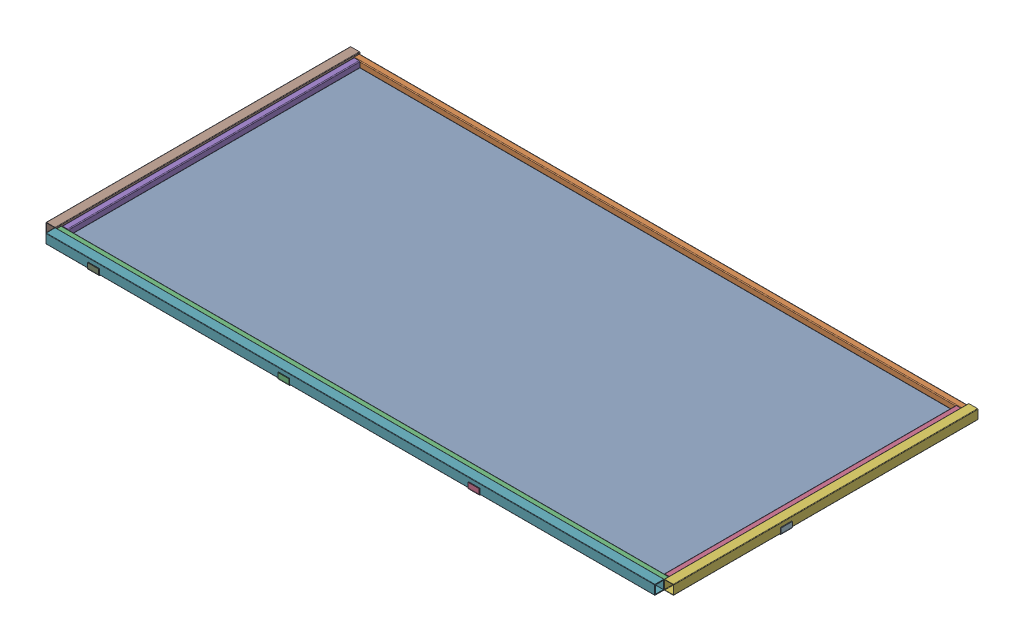
SolidWorks assembly Roof Assembly, configuration Default. Lengths in mm.
Overall size (2520.95 41.27 1263.65).
16 component instances, 6 part files, 34 mates.
Components (placement in the parent):
- Polycarbonate-1: Polycarbonate [8574K75] at (-1219.2 3.175 -609.6) x (1 0 0) z (0 -1 0) size (2438.4 1219.2 6.35)
- 8ft 1in Steel Bar-1: 8ft 1in Steel Bar [1471T534] at (-1219.2 19.05 -1206.5) x (0 0 1) z (-1 0 0) size (25.4 25.4 2438.4)
- 8ft 1in Steel Bar-2: 8ft 1in Steel Bar [1471T534] at (-1219.2 19.05 -12.7) x (0 0 1) z (-1 0 0) size (25.4 25.4 2438.4)
- 46in 1in Steel Bar-1: 46in 1in Steel Bar [1471T532] at (-12.7 19.05 -635) size (25.4 25.4 1168.4)
- 46in 1in Steel Bar-2: 46in 1in Steel Bar [1471T532] at (-2425.7 19.05 -635) size (25.4 25.4 1168.4)
- 4ft 1.5in Steel Bar-1: 4ft 1.5in Steel Bar [6527K573] at (19.05 19.05 -304.8) x (0 0 -1) z (1 0 0) size (1219.2 38.1 38.1)
- 8ft 1.5in Steel Bar-1: 8ft 1.5in Steel Bar [1984N13] at (-1219.2 19.05 19.05) x (0 0 1) z (-1 0 0) size (38.1 38.1 2438.4)
- 4ft 1.5in Steel Bar-3: 4ft 1.5in Steel Bar [6527K573] at (-2457.45 19.05 -304.8) x (0 0 -1) z (0 -1 0) size (1219.2 38.1 38.1)
- Corner Bracket-1: Corner Bracket [2313N38] at (-2246.5399 -3.175 -9.525) x (0 1 0) z (0 0 -1) size (25.4 44.45 50.8)
- Corner Bracket-2: Corner Bracket [2313N38] at (-2246.5399 -3.175 -1171.575) x (0 1 0) z (0 0 1) size (25.4 44.45 50.8)
- Corner Bracket-7: Corner Bracket [2313N38] at (-2428.875 -3.175 -449.8508) x (0 1 0) z (1 0 0) size (25.4 44.45 50.8)
- Corner Bracket-8: Corner Bracket [2313N38] at (-9.525 -3.175 -449.8508) x (0 1 0) z (-1 0 0) size (25.4 44.45 50.8)
- Corner Bracket-3: Corner Bracket [2313N38] at (-1484.5399 -3.175 -1171.575) x (0 1 0) z (0 0 1) size (25.4 44.45 50.8)
- Corner Bracket-4: Corner Bracket [2313N38] at (-722.5399 -3.175 -1171.575) x (0 1 0) z (0 0 1) size (25.4 44.45 50.8)
- Corner Bracket-5: Corner Bracket [2313N38] at (-1484.5399 -3.175 -9.525) x (0 1 0) z (0 0 -1) size (25.4 44.45 50.8)
- Corner Bracket-6: Corner Bracket [2313N38] at (-722.5399 -3.175 -9.525) x (0 1 0) z (0 0 -1) size (25.4 44.45 50.8)
Mates (geometry in assembly coordinates):
- Coincident1: coincident anti-aligned: plane of 8574K75_Clear Impact-Resistant Polycarbonate-1 through (-1219.2 0 -609.6) normal (0 -1 0)
- Coincident2: coincident aligned: plane of 8574K75_Clear Impact-Resistant Polycarbonate-1 through (-2438.4 0 0) normal (0 0 1)
- Coincident3: coincident aligned: plane of 8574K75_Clear Impact-Resistant Polycarbonate-1 through (0 0 -1219.2) normal (1 0 0)
- Coincident4: coincident anti-aligned: plane of 8574K75_Clear Impact-Resistant Polycarbonate-1 through (-1219.2 6.35 -609.6) normal (0 1 0); plane of 8ft Steel Bar-1 through (-2438.4 6.35 -1193.8) normal (0 -1 0)
- Coincident6: coincident aligned: plane of 8574K75_Clear Impact-Resistant Polycarbonate-1 through (0 0 -1219.2) normal (1 0 0); plane of 8ft Steel Bar-1 through (0 19.05 -1206.5) normal (1 0 0)
- Coincident7: coincident aligned: plane of 8ft Steel Bar-1 through (-2438.4 31.75 -1193.8) normal (0 1 0); plane of 46in Steel Bar-1 through (0 31.75 -25.4) normal (0 1 0)
- Coincident8: coincident aligned: plane of 8574K75_Clear Impact-Resistant Polycarbonate-1 through (-2438.4 0 -1219.2) normal (0 0 -1); plane of 8ft Steel Bar-1 through (-2438.4 6.35 -1219.2) normal (0 0 -1)
- Coincident9: coincident anti-aligned: plane of 8ft Steel Bar-1 through (-2438.4 6.35 -1193.8) normal (0 0 1); plane of 46in Steel Bar-1 through (-25.4 6.35 -1193.8) normal (0 0 -1)
- Coincident10: coincident aligned: plane of 8ft Steel Bar-1 through (0 19.05 -1206.5) normal (1 0 0); plane of 46in Steel Bar-1 through (0 6.35 -25.4) normal (1 0 0)
- Coincident11: coincident anti-aligned: plane of 8574K75_Clear Impact-Resistant Polycarbonate-1 through (-1219.2 6.35 -609.6) normal (0 1 0); plane of 8ft Steel Bar-2 through (-2438.4 6.35 0) normal (0 -1 0)
- Coincident12: coincident anti-aligned: plane of 8574K75_Clear Impact-Resistant Polycarbonate-1 through (-1219.2 6.35 -609.6) normal (0 1 0); plane of 46in Steel Bar-2 through (-2413 6.35 -25.4) normal (0 -1 0)
- Coincident13: coincident aligned: plane of 8ft Steel Bar-1 through (-2438.4 19.05 -1206.5) normal (-1 0 0); plane of 46in Steel Bar-2 through (-2438.4 6.35 -25.4) normal (-1 0 0)
- Coincident14: coincident anti-aligned: plane of 8ft Steel Bar-1 through (-2438.4 6.35 -1193.8) normal (0 0 1); plane of 46in Steel Bar-2 through (-2438.4 6.35 -1193.8) normal (0 0 -1)
- Coincident15: coincident anti-aligned: plane of 8ft Steel Bar-2 through (-2438.4 6.35 -25.4) normal (0 0 -1); plane of 46in Steel Bar-1 through (-12.7 19.05 -25.4) normal (0 0 1)
- Coincident16: coincident aligned: plane of 8ft Steel Bar-2 through (0 19.05 -12.7) normal (1 0 0); plane of 46in Steel Bar-1 through (0 6.35 -25.4) normal (1 0 0)
- Coincident17: coincident anti-aligned: plane of 46in Steel Bar-1 through (0 6.35 -25.4) normal (1 0 0); plane of 6527K573_Low-Carbon Steel Rectangular Tube-1 through (0 1.905 -1219.2) normal (-1 0 0)
- Coincident18: coincident aligned: plane of 8574K75_Clear Impact-Resistant Polycarbonate-1 through (-1219.2 0 -609.6) normal (0 -1 0); plane of 6527K573_Low-Carbon Steel Rectangular Tube-1 through (1.905 0 -1219.2) normal (0 -1 0)
- Coincident19: coincident aligned: plane of 8ft Steel Bar-2 through (-2438.4 6.35 0) normal (0 0 1); plane of 6527K573_Low-Carbon Steel Rectangular Tube-1 through (0 38.1 0) normal (0 0 1)
- Coincident20: coincident aligned: plane of 8574K75_Clear Impact-Resistant Polycarbonate-1 through (-1219.2 0 -609.6) normal (0 -1 0); plane of 1984N13_Weld-Together Framing Rail-1 through (-2438.4 0 0) normal (0 -1 0)
- Coincident21: coincident anti-aligned: plane of 8ft Steel Bar-2 through (-2438.4 6.35 0) normal (0 0 1); plane of 1984N13_Weld-Together Framing Rail-1 through (-2438.4 0 0) normal (0 0 -1)
- Coincident22: coincident aligned: plane of 8ft Steel Bar-2 through (-2438.4 19.05 -12.7) normal (-1 0 0); plane of 1984N13_Weld-Together Framing Rail-1 through (-2438.4 19.05 19.05) normal (-1 0 0)
- Coincident23: coincident anti-aligned: plane of 46in Steel Bar-2 through (-2438.4 6.35 -25.4) normal (-1 0 0); plane of 6527K573_Low-Carbon Steel Rectangular Tube-3 through (-2438.4 36.195 -1219.2) normal (1 0 0)
- Coincident25: coincident aligned: plane of 8ft Steel Bar-1 through (-2438.4 6.35 -1219.2) normal (0 0 -1); plane of 6527K573_Low-Carbon Steel Rectangular Tube-3 through (-2474.595 36.195 -1219.2) normal (0 0 -1)
- Coincident26: coincident aligned: plane of 8574K75_Clear Impact-Resistant Polycarbonate-1 through (-1219.2 0 -609.6) normal (0 -1 0); plane of 6527K573_Low-Carbon Steel Rectangular Tube-3 through (-2474.595 0 -1219.2) normal (0 -1 0)
- Coincident27: coincident anti-aligned: plane of 8ft 1.5in Steel Bar-1 through (-2438.4 0 38.1) normal (0 0 1); plane of Corner Bracket-1 through (-2268.7649 -3.175 38.1) normal (0 0 -1)
- Coincident28: coincident anti-aligned: plane of Polycarbonate-1 through (-1219.2 0 -609.6) normal (0 -1 0); plane of Corner Bracket-1 through (-2268.7649 0 -9.525) normal (0 1 0)
- Coincident29: coincident anti-aligned: plane of 8ft 1in Steel Bar-1 through (-2438.4 6.35 -1219.2) normal (0 0 -1); plane of Corner Bracket-2 through (-2224.3149 -3.175 -1219.2) normal (0 0 1)
- Coincident30: coincident anti-aligned: plane of Polycarbonate-1 through (-1219.2 0 -609.6) normal (0 -1 0); plane of Corner Bracket-2 through (-2224.3149 0 -1171.575) normal (0 1 0)
- Coincident31: coincident aligned: plane of Corner Bracket-1 through (-2268.7649 -3.175 38.1) normal (-1 0 0); plane of Corner Bracket-2 through (-2268.7649 -3.175 -1219.2) normal (-1 0 0)
- Coincident32: coincident anti-aligned: plane of Polycarbonate-1 through (-1219.2 0 -609.6) normal (0 -1 0); plane of Corner Bracket-8 through (-9.525 0 -427.6258) normal (0 1 0)
- Coincident33: coincident anti-aligned: plane of 4ft 1.5in Steel Bar-1 through (38.1 1.905 -1219.2) normal (1 0 0); plane of Corner Bracket-8 through (38.1 -3.175 -427.6258) normal (-1 0 0)
- Coincident34: coincident anti-aligned: plane of Polycarbonate-1 through (-1219.2 0 -609.6) normal (0 -1 0); plane of Corner Bracket-7 through (-2428.875 0 -472.0758) normal (0 1 0)
- Coincident35: coincident anti-aligned: plane of 4ft 1.5in Steel Bar-3 through (-2476.5 36.195 -1219.2) normal (-1 0 0); plane of Corner Bracket-7 through (-2476.5 -3.175 -472.0758) normal (1 0 0)
- Coincident36: coincident aligned: plane of Corner Bracket-7 through (-2476.5 -3.175 -472.0758) normal (0 0 -1); plane of Corner Bracket-8 through (38.1 -3.175 -472.0758) normal (0 0 -1)
